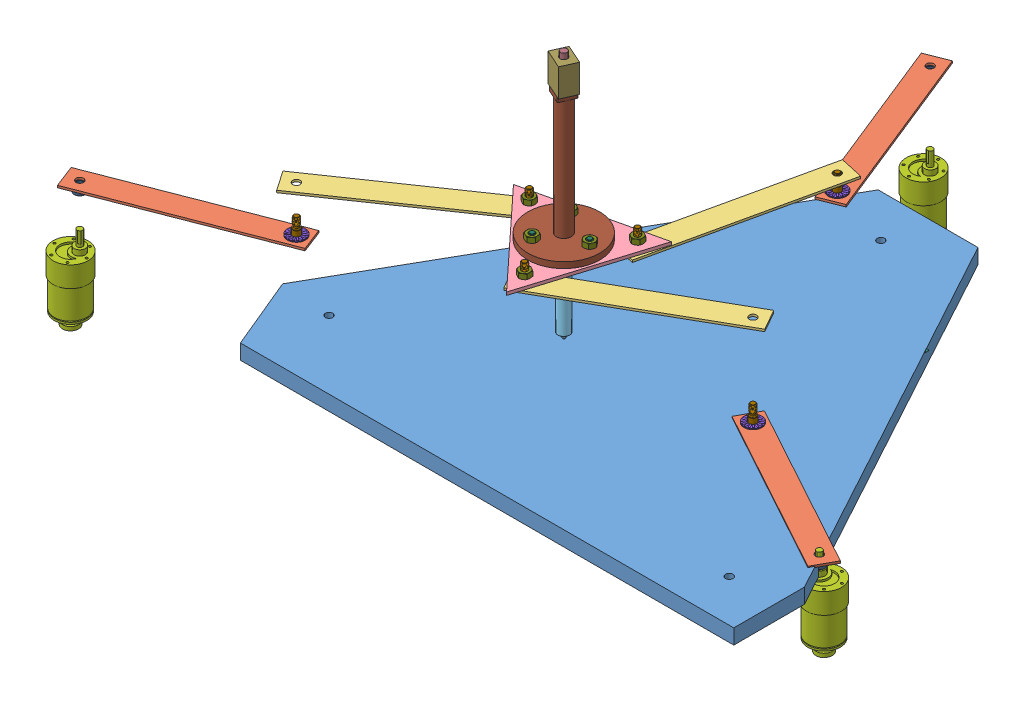
SolidWorks assembly 10_Full_3R_Assembly_rev4, configuration Default. Lengths in mm.
Overall size (748.91 360.76 573.39).
42 component instances, 16 part files, 95 mates.
Components (placement in the parent):
- 01_Base_Plate_rev4-1: 01_Base_Plate_rev4 [Default] at (-311.7855 -6.35 287.7555) size (555.85 15.88 479.43)
- 02_A_Link-1: 02_A_Link [Default] at (-1028.1586 56.8301 289.4507) x (0.932403 0 -0.361422) z (0.361422 0 0.932403) size (203.2 2.29 25.4)
- 03_B_Link-1: 03_B_Link [Default] at (-858.3965 105.6473 226.4186) x (0.824045 0 -0.566525) z (0.566525 0 0.824045) size (203.2 2.29 25.4)
- 02_A_Link-2: 02_A_Link [Default] at (-506.0967 8.3926 95.3531) x (0.877039 0 0.48042) z (-0.48042 0 0.877039) size (203.2 2.29 25.4)
- 03_B_Link-2: 03_B_Link [Default] at (-648.0718 105.6473 195.683) x (0.868786 0 -0.495189) z (0.495189 0 0.868786) size (203.2 2.29 25.4)
- 02_A_Link-3: 02_A_Link [Default] at (-635.8686 90.8532 -268.3939) x (0.373245 0 0.927733) z (0.927733 0 -0.373245) size (203.2 2.29 25.4)
- 03_B_Link-3: 03_B_Link [Default] at (-605.4137 105.6473 101.8075) x (0.216611 0 -0.976258) z (0.976258 0 0.216611) size (203.2 2.29 25.4)
- 04_Platform-1: 04_Platform [Default] at (-732.8839 109.9177 100.5485) x (0.680323 0 0.732913) z (-0.732913 0 0.680323) size (139.95 3.17 121.2)
- 05_Pen-1: 05_Pen [Default] at (-655.6663 21.9604 124.3496) x (-0.946735 0 0.322013) z (-0.322013 0 -0.946735) size (12.7 123.83 12.7)
- 06_Paper-1: 06_Paper [Default] at (-679.8568 8.7347 207.5281) size (215.9 0.25 279.4)
- 07_Motor_rev2-1: 07_Motor_rev2 [Default] at (-649.9106 -74.05 -251.8611) x (0 -1 0) z (0.001482 0 0.999999) size (88.7 37 37)
- 07_Motor_rev2-2: 07_Motor_rev2 [Default] at (-1026.5606 -74.05 277.1468) x (0 -1 0) z (0.589672 0 0.807643) size (88.7 37 37)
- 07_Motor_rev2-3: 07_Motor_rev2 [Default] at (-326.1577 -74.05 177.5449) x (0 -1 0) z (0.25861 0 -0.965982) size (88.7 37 37)
- 5909K24_Needle-Roller Thrust Bearing-1: 5909K24_Needle-Roller Thrust Bearing [5909K24] at (-576.5477 91.8454 -86.9206) x (-0.973754 0 -0.227603) z (0.227603 0 -0.973754) size (19.05 1.98 19.05)
- 91259A576_Alloy Steel Shoulder Screw-1: 91259A576_Alloy Steel Shoulder Screw [91259A576] at (-576.5477 83.0109 -86.9206) x (0.154475 0 0.987997) z (0 -1 0) size (11.11 11.11 26.95)
- 5909K24_Needle-Roller Thrust Bearing-3: 5909K24_Needle-Roller Thrust Bearing [5909K24] at (-855.1259 60.1083 208.7584) x (0.9423 0 0.334769) z (-0.334769 0 0.9423) size (19.05 1.98 19.05)
- 5909K24_Needle-Roller Thrust Bearing-4: 5909K24_Needle-Roller Thrust Bearing [5909K24] at (-488.857 11.6708 90.316) x (0.999962 0 -0.008701) z (0.008701 0 0.999962) size (19.05 1.98 19.05)
- 91259A576_Alloy Steel Shoulder Screw-2: 91259A576_Alloy Steel Shoulder Screw [91259A576] at (-855.1259 51.2739 208.7584) x (0.890655 0 -0.45468) z (0 -1 0) size (11.11 11.11 26.95)
- 91259A576_Alloy Steel Shoulder Screw-3: 91259A576_Alloy Steel Shoulder Screw [91259A576] at (-488.857 2.8363 90.316) x (0.621536 0 -0.783386) z (0 -1 0) size (11.11 11.11 26.95)
- 91259A576_Alloy Steel Shoulder Screw-4: 91259A576_Alloy Steel Shoulder Screw [91259A576] at (-708.6108 100.091 108.0303) x (-0.287715 0 -0.957716) z (0 -1 0) size (11.11 11.11 26.95)
- 91259A576_Alloy Steel Shoulder Screw-5: 91259A576_Alloy Steel Shoulder Screw [91259A576] at (-643.3271 100.091 178.3605) x (0.554326 0 -0.8323) z (0 -1 0) size (11.11 11.11 26.95)
- 91259A576_Alloy Steel Shoulder Screw-6: 91259A576_Alloy Steel Shoulder Screw [91259A576] at (-615.0612 100.091 86.6581) x (0.999981 0 0.006147) z (0 -1 0) size (11.11 11.11 26.95)
- 5909K24_Needle-Roller Thrust Bearing-5: 5909K24_Needle-Roller Thrust Bearing [5909K24] at (-708.6108 108.9255 108.0303) x (0.997045 0 0.076824) z (-0.076824 0 0.997045) size (19.05 1.98 19.05)
- 5909K24_Needle-Roller Thrust Bearing-6: 5909K24_Needle-Roller Thrust Bearing [5909K24] at (-615.0612 108.9255 86.6581) x (0.994154 0 -0.107968) z (0.107968 0 0.994154) size (19.05 1.98 19.05)
- 5909K24_Needle-Roller Thrust Bearing-7: 5909K24_Needle-Roller Thrust Bearing [5909K24] at (-643.3271 108.9255 178.3605) x (0.969179 0 -0.246358) z (0.246358 0 0.969179) size (19.05 1.98 19.05)
- 6056N14_Carbon Steel Set Screw Collar-1: 6056N14_Carbon Steel Set Screw Collar [6056N14] at (-1020.9071 52.8301 273.0191) x (-0.584369 0 0.811488) z (0 1 0) size (12 12.47 8)
- 6056N14_Carbon Steel Set Screw Collar-2: 6056N14_Carbon Steel Set Screw Collar [6056N14] at (-642.9106 84.5672 -251.8715) x (0.948137 0 -0.317863) z (0 1 0) size (12 12.47 8)
- 6056N14_Carbon Steel Set Screw Collar-3: 6056N14_Carbon Steel Set Screw Collar [6056N14] at (-332.9195 4.3926 175.7347) x (0.999426 0 0.033886) z (0 -1 0) size (12 12.47 8)
- PenHolder-1: PenHolder [Default] at (-655.6663 113.0927 124.3496) x (-0.407207 0 0.913336) z (-0.913336 0 -0.407207) size (76.2 138.35 76.2)
- SolenoidAssembly-1: SolenoidAssembly [Default] at (-617.3347 234.5732 124.9461) x (-0.407207 0 0.913336) z (-0.913336 0 -0.407207) size (17 55.9 22)
  - Solenoid_Mount-2: Solenoid_Mount [Default] at (6.5641 46.5695 46.2525) x (1 0 0) z (0 0 -1) size (17 29.7 22)
  - Solenoid_Shaft-1: Solenoid_Shaft [Default] at (15.0641 0.2373 35.2525) x (-0.773677 0 0.63358) z (-0.63358 0 -0.773677) size (6.9 51.9 6.9)
  - Solenoid_Cap-1: Solenoid_Cap [Default] at (15.0641 -3.7627 35.2525) x (0.200587 0 -0.979676) z (0.979676 0 0.200587) size (5 12 5)
- 90604A539_Pan Head Combination Phillips Slotted Screws-1: 90604A539_Pan Head Combination Phillips Slotted Screws [90604A539] at (-670.1692 125.7927 103.4971) x (-0.886591 0 -0.462554) z (0 -1 0) size (12.5 12.5 20.66)
- 90604A539_Pan Head Combination Phillips Slotted Screws-2: 90604A539_Pan Head Combination Phillips Slotted Screws [90604A539] at (-666.4738 125.7927 147.3357) x (0.746863 0 0.664978) z (0 -1 0) size (12.5 12.5 20.66)
- 90604A539_Pan Head Combination Phillips Slotted Screws-3: 90604A539_Pan Head Combination Phillips Slotted Screws [90604A539] at (-630.3561 125.7927 122.2161) x (1 0 0) z (0 -1 0) size (12.5 12.5 20.66)
- 95462A029_Medium-Strength Steel Hex Nut-1: 95462A029_Medium-Strength Steel Hex Nut [95462A029] at (-630.3561 122.2208 122.2161) x (-0.145713 0 -0.989327) z (0 -1 0) size (11.11 12.83 6.51)
- 95462A029_Medium-Strength Steel Hex Nut-2: 95462A029_Medium-Strength Steel Hex Nut [95462A029] at (-643.3271 115.8708 178.3605) x (-1 0 0) z (0 1 0) size (11.11 12.83 6.51)
- 95462A029_Medium-Strength Steel Hex Nut-3: 95462A029_Medium-Strength Steel Hex Nut [95462A029] at (-670.1692 122.2208 103.4971) x (-1 0 0) z (0 1 0) size (11.11 12.83 6.51)
- 95462A029_Medium-Strength Steel Hex Nut-4: 95462A029_Medium-Strength Steel Hex Nut [95462A029] at (-708.6108 115.8708 108.0303) x (-1 0 0) z (0 1 0) size (11.11 12.83 6.51)
- 95462A029_Medium-Strength Steel Hex Nut-5: 95462A029_Medium-Strength Steel Hex Nut [95462A029] at (-615.0612 115.8708 86.6581) x (-1 0 0) z (0 1 0) size (11.11 12.83 6.51)
- 95462A029_Medium-Strength Steel Hex Nut-6: 95462A029_Medium-Strength Steel Hex Nut [95462A029] at (-666.4738 122.2208 147.3357) x (-0.377684 0 0.925934) z (0 -1 0) size (11.11 12.83 6.51)
Mates (geometry in assembly coordinates):
- Concentric4: concentric anti-aligned: circle of 04_Platform-1; circle of 05_Pen-1
- Tangent1: tangent anti-aligned: plane of 06_Paper-1 through (-679.8568 8.9887 207.5281) normal (0 1 0); sphere of 08_Roller-1
- Tangent2: tangent anti-aligned: plane of 06_Paper-1 through (-679.8568 8.9887 207.5281) normal (0 1 0); sphere of 08_Roller-2
- Tangent3: tangent anti-aligned: plane of 06_Paper-1 through (-679.8568 8.9887 207.5281) normal (0 1 0); sphere of 08_Roller-3
- Tangent4: tangent anti-aligned: plane of 04_Platform-1 through (-732.8839 109.9177 100.5485) normal (0 -1 0); sphere of 08_Roller-1
- Coincident37: coincident anti-aligned: plane of 02_A_Link-3 through (-635.8686 88.5672 -268.3939) normal (0 -1 0); plane of 07_Motor-3 through (15.6523 48.5738 -175.9022) normal (0 1 0)
- Concentric8: concentric aligned: circle of 02_A_Link-3; circle of 07_Motor-3
- Concentric12: concentric anti-aligned: circle of 04_Platform-1; circle of 10_Ball_Transfer-2/09_Ball_Holder-1
- Concentric23: concentric anti-aligned: circle of 02_A_Link-1; circle of 07_Motor_rev2-2
- Concentric24: concentric anti-aligned: circle of 02_A_Link-2; circle of 07_Motor_rev2-3
- Concentric25: concentric aligned: circle of 02_A_Link-3; circle of 07_Motor_rev2-1
- Concentric26: concentric anti-aligned: cylinder of 07_Motor_rev2-1 through (-649.9106 6.0614 -251.8611) axis (0 1 0) radius 18.5; cylinder of Motor_Mount-1 through (18.4145 -100.9975 -177.0726) axis (0 -1 0) radius 20.6375
- Concentric29: concentric aligned: cylinder of 03_B_Link-3 through (-576.5477 105.6473 -86.9206) axis (0 1 0) radius 3.9688; cylinder of 91259A427_Alloy Steel Shoulder Screw-1 through (-164.7374 27.7812 -154.398) axis (0 1 0) radius 3.9688
- Concentric30: concentric aligned: cylinder of 02_A_Link-3 through (-576.5477 90.8532 -86.9206) axis (0 -1 0) radius 3.9688; cylinder of 5909K24_Needle-Roller Thrust Bearing-1 through (-576.5477 90.8532 -86.9206) axis (0 -1 0) radius 3.9624
- Tangent7: tangent anti-aligned: plane of 02_A_Link-3 through (-635.8686 90.8532 -268.3939) normal (0 1 0); cylinder of 5909K24_Needle-Roller Thrust Bearing-1 through (-570.1082 91.8454 -80.8828) axis (0.729494 0 0.683987) radius 0.9922
- Coincident58: coincident anti-aligned: plane of 07_Motor_rev2-1 through (-632.6606 -28.25 -251.8867) normal (0 -1 0); plane of Motor_Mount-1 through (3.4631 -22.225 -165.2677) normal (0 1 0)
- Concentric32: concentric anti-aligned: cylinder of 02_A_Link-3 through (-576.5477 90.8532 -86.9206) axis (0 -1 0) radius 3.9688; cylinder of 03_B_Link-3 through (-576.5477 105.6473 -86.9206) axis (0 1 0) radius 3.9688
- Concentric33: concentric anti-aligned: circle of 03_B_Link-3; circle of 5909K24_Needle-Roller Thrust Bearing-2
- Tangent10: tangent anti-aligned: plane of 5909K24_Needle-Roller Thrust Bearing-1 through (-574.3798 92.3415 -96.1956) normal (0 1 0); cylinder of 5909K24_Needle-Roller Thrust Bearing-2 through (-163.8488 16.8055 -163.1804) axis (0.100661 0 -0.994921) radius 0.9922
- Concentric34: concentric aligned: circle of 03_B_Link-3; circle of 91259A175_Alloy Steel Shoulder Screw-1
- Concentric36: concentric aligned: circle of 03_B_Link-3; circle of 91259A576_Alloy Steel Shoulder Screw-1
- Concentric37: concentric aligned: circle of 02_A_Link-2; circle of 03_B_Link-2
- Concentric38: concentric aligned: circle of 02_A_Link-1; circle of 03_B_Link-1
- Concentric39: concentric anti-aligned: cylinder of 02_A_Link-2 through (-488.857 8.3926 90.316) axis (0 1 0) radius 3.9688; cylinder of 5909K24_Needle-Roller Thrust Bearing-4 through (-488.857 10.6786 90.316) axis (0 -1 0) radius 3.9624
- Tangent13: tangent anti-aligned: plane of 02_A_Link-2 through (-506.0967 10.6786 95.3531) normal (0 1 0); cylinder of 5909K24_Needle-Roller Thrust Bearing-4 through (-492.3771 11.6708 98.4111) axis (-0.398773 0 0.91705) radius 0.9922
- Concentric43: concentric anti-aligned: cylinder of 03_B_Link-1 through (-855.1259 105.6473 208.7584) axis (0 1 0) radius 3.9688; cylinder of 5909K24_Needle-Roller Thrust Bearing-3 through (-855.1259 59.1161 208.7584) axis (0 -1 0) radius 3.9624
- Tangent15: tangent anti-aligned: plane of 02_A_Link-1 through (-1028.1586 59.1161 289.4507) normal (0 1 0); cylinder of 5909K24_Needle-Roller Thrust Bearing-3 through (-860.852 60.1083 202.0402) axis (-0.648671 0 -0.761069) radius 0.9922
- Concentric44: concentric aligned: cylinder of 03_B_Link-2 through (-488.857 105.6473 90.316) axis (0 1 0) radius 3.9688; cylinder of 91259A576_Alloy Steel Shoulder Screw-3 through (-488.857 29.0301 90.316) axis (0 1 0) radius 3.9688
- Coincident71: coincident anti-aligned: plane of 02_A_Link-3 through (-635.8686 88.5672 -268.3939) normal (0 -1 0); plane of 91259A576_Alloy Steel Shoulder Screw-1 through (-571.0581 88.5672 -87.7789) normal (0 1 0)
- Coincident72: coincident anti-aligned: plane of 02_A_Link-2 through (-506.0967 8.3926 95.3531) normal (0 -1 0); plane of 91259A576_Alloy Steel Shoulder Screw-3 through (-493.2097 8.3926 86.8626) normal (0 1 0)
- Coincident73: coincident anti-aligned: plane of 02_A_Link-1 through (-1028.1586 56.8301 289.4507) normal (0 -1 0); plane of 91259A576_Alloy Steel Shoulder Screw-2 through (-857.6523 56.8301 203.8097) normal (0 1 0)
- Concentric45: concentric aligned: cylinder of 02_A_Link-1 through (-855.1259 56.8301 208.7584) axis (0 1 0) radius 3.9688; cylinder of 91259A576_Alloy Steel Shoulder Screw-2 through (-855.1259 77.4676 208.7584) axis (0 1 0) radius 3.9688
- Concentric46: concentric aligned: cylinder of 07_Motor_rev2-2 through (-1020.9071 -74.05 273.0191) axis (0 -1 0) radius 3; cylinder of 98541A114_External Retaining Ring-1 through (-200.6826 18.389 208.8764) axis (0 -1 0) radius 2.8
- Coincident74: coincident anti-aligned: plane of 02_A_Link-1 through (-1028.1586 56.8301 289.4507) normal (0 -1 0); plane of 98541A114_External Retaining Ring-1 through (-200.6826 18.389 208.8764) normal (0 1 0)
- Concentric49: concentric anti-aligned: cylinder of 03_B_Link-2 through (-643.3271 105.6473 178.3605) axis (0 1 0) radius 3.9688; cylinder of 04_Platform-1 through (-643.3271 113.0927 178.3605) axis (0 -1 0) radius 3.9688
- Concentric50: concentric anti-aligned: cylinder of 03_B_Link-1 through (-708.6108 105.6473 108.0303) axis (0 1 0) radius 3.9688; cylinder of 04_Platform-1 through (-708.6108 113.0927 108.0303) axis (0 -1 0) radius 3.9688
- Concentric51: concentric anti-aligned: cylinder of 03_B_Link-3 through (-615.0612 105.6473 86.6581) axis (0 1 0) radius 3.9688; cylinder of 04_Platform-1 through (-615.0612 113.0927 86.6581) axis (0 -1 0) radius 3.9688
- Coincident78: coincident anti-aligned: plane of 04_Platform-1 through (-732.8839 109.9177 100.5485) normal (0 -1 0); plane of Spacer_Platform-1 through (19.8558 28.0458 18.7709) normal (0 1 0)
- Coincident79: coincident anti-aligned: plane of 10_Ball_Transfer-2/09_Ball_Holder-1 through (-104.8331 16.9333 22.1387) normal (0 1 0); plane of Spacer_Platform-2 through (-4.1341 20.1083 60.3228) normal (0 -1 0)
- Concentric53: concentric anti-aligned: circle of 10_Ball_Transfer-2/09_Ball_Holder-1; circle of Spacer_Platform-2
- Parallel4: parallel anti-aligned: plane of 03_B_Link-2 through (-648.0718 107.9333 195.683) normal (0 1 0); plane of 04_Platform-1 through (-732.8839 109.9177 100.5485) normal (0 -1 0)
- Parallel5: parallel aligned: plane of 03_B_Link-1 through (-858.3965 107.9333 226.4186) normal (0 1 0); plane of 04_Platform-1 through (-732.8839 113.0927 100.5485) normal (0 1 0)
- Parallel6: parallel aligned: plane of 03_B_Link-3 through (-605.4137 107.9333 101.8075) normal (0 1 0); plane of 04_Platform-1 through (-732.8839 113.0927 100.5485) normal (0 1 0)
- Coincident85: coincident anti-aligned: plane of 03_B_Link-1 through (-858.3965 105.6473 226.4186) normal (0 -1 0); plane of 91259A576_Alloy Steel Shoulder Screw-4 through (-713.9321 105.6473 109.6289) normal (0 1 0)
- Concentric55: concentric aligned: cylinder of 03_B_Link-1 through (-708.6108 105.6473 108.0303) axis (0 1 0) radius 3.9688; cylinder of 91259A576_Alloy Steel Shoulder Screw-4 through (-708.6108 126.2848 108.0303) axis (0 1 0) radius 3.9688
- Concentric56: concentric anti-aligned: cylinder of 91259A576_Alloy Steel Shoulder Screw-4 through (-708.6108 126.2848 108.0303) axis (0 1 0) radius 3.9688; cylinder of 5909K24_Needle-Roller Thrust Bearing-5 through (-708.6108 107.9333 108.0303) axis (0 -1 0) radius 3.9624
- Tangent20: tangent anti-aligned: plane of 03_B_Link-1 through (-858.3965 107.9333 226.4186) normal (0 1 0); cylinder of 5909K24_Needle-Roller Thrust Bearing-5 through (-715.6051 108.9255 113.4155) axis (-0.792354 0 0.610061) radius 0.9922
- Concentric57: concentric anti-aligned: cylinder of 04_Platform-1 through (-643.3271 113.0927 178.3605) axis (0 -1 0) radius 3.9688; cylinder of 91259A576_Alloy Steel Shoulder Screw-5 through (-643.3271 126.2848 178.3605) axis (0 1 0) radius 3.9688
- Coincident86: coincident anti-aligned: plane of 03_B_Link-2 through (-648.0718 105.6473 195.683) normal (0 -1 0); plane of 91259A576_Alloy Steel Shoulder Screw-5 through (-647.9516 105.6473 175.2806) normal (0 1 0)
- Concentric58: concentric anti-aligned: cylinder of 04_Platform-1 through (-615.0612 113.0927 86.6581) axis (0 -1 0) radius 3.9688; cylinder of 91259A576_Alloy Steel Shoulder Screw-6 through (-615.0612 126.2848 86.6581) axis (0 1 0) radius 3.9688
- Concentric59: concentric anti-aligned: cylinder of 91259A576_Alloy Steel Shoulder Screw-5 through (-643.3271 126.2848 178.3605) axis (0 1 0) radius 3.9688; cylinder of 5909K24_Needle-Roller Thrust Bearing-7 through (-643.3271 107.9333 178.3605) axis (0 -1 0) radius 3.9624
- Tangent24: tangent anti-aligned: plane of 03_B_Link-2 through (-648.0718 107.9333 195.683) normal (0 1 0); cylinder of 5909K24_Needle-Roller Thrust Bearing-7 through (-641.1524 108.9255 186.9158) axis (0.246358 0 0.969179) radius 0.9922
- Concentric60: concentric anti-aligned: cylinder of 91259A576_Alloy Steel Shoulder Screw-6 through (-615.0612 126.2848 86.6581) axis (0 1 0) radius 3.9688; cylinder of 5909K24_Needle-Roller Thrust Bearing-6 through (-615.0612 107.9333 86.6581) axis (0 -1 0) radius 3.9624
- Tangent25: tangent anti-aligned: plane of 03_B_Link-3 through (-605.4137 107.9333 101.8075) normal (0 1 0); cylinder of 5909K24_Needle-Roller Thrust Bearing-6 through (-606.4332 108.9255 84.7929) axis (0.977423 0 -0.211294) radius 0.9922
- Coincident88: coincident anti-aligned: plane of 03_B_Link-3 through (-605.4137 105.6473 101.8075) normal (0 -1 0); plane of 91259A576_Alloy Steel Shoulder Screw-6 through (-615.027 105.6473 81.1019) normal (0 1 0)
- Concentric61: concentric anti-aligned: cylinder of 07_Motor_rev2-1 through (-642.9106 -74.05 -251.8715) axis (0 -1 0) radius 3; cylinder of grainger-2alx5-1 through (24.5848 9.389 -180.3783) axis (0 1 0) radius 1.5
- Coincident89: coincident anti-aligned: plane of 02_A_Link-3 through (-635.8686 88.5672 -268.3939) normal (0 -1 0); plane of grainger-2alx5-1 through (24.5848 18.389 -180.3783) normal (0 1 0)
- Concentric62: concentric anti-aligned: cylinder of 07_Motor_rev2-3 through (-332.9195 -74.05 175.7347) axis (0 -1 0) radius 3; cylinder of grainger-2alx5-2 through (238.4578 9.389 207.6961) axis (0 1 0) radius 1.5
- Coincident90: coincident anti-aligned: plane of 02_A_Link-2 through (-506.0967 8.3926 95.3531) normal (0 -1 0); plane of grainger-2alx5-2 through (238.4578 18.389 207.6961) normal (0 1 0)
- Concentric63: concentric anti-aligned: cylinder of 07_Motor_rev2-2 through (-1020.9071 -74.05 273.0191) axis (0 -1 0) radius 3; cylinder of grainger-2alx5-3 through (-199.783 9.389 210.9877) axis (0 1 0) radius 1.5
- Coincident91: coincident anti-aligned: plane of 02_A_Link-1 through (-1028.1586 56.8301 289.4507) normal (0 -1 0); plane of grainger-2alx5-3 through (-199.783 18.389 210.9877) normal (0 1 0)
- Concentric64: concentric aligned: cylinder of 07_Motor_rev2-2 through (-1020.9071 -74.05 273.0191) axis (0 -1 0) radius 3; cylinder of 6056N14_Carbon Steel Set Screw Collar-1 through (-1020.9071 56.8301 273.0191) axis (0 -1 0) radius 3
- Coincident92: coincident anti-aligned: plane of 02_A_Link-1 through (-1028.1586 56.8301 289.4507) normal (0 -1 0); plane of 6056N14_Carbon Steel Set Screw Collar-1 through (-1020.9071 56.8301 273.0191) normal (0 1 0)
- Concentric65: concentric anti-aligned: cylinder of 07_Motor_rev2-3 through (-332.9195 -74.05 175.7347) axis (0 -1 0) radius 3; cylinder of 6056N14_Carbon Steel Set Screw Collar-3 through (-332.9195 0.3926 175.7347) axis (0 1 0) radius 3
- Coincident93: coincident anti-aligned: plane of 02_A_Link-2 through (-506.0967 8.3926 95.3531) normal (0 -1 0); plane of 6056N14_Carbon Steel Set Screw Collar-3 through (-332.9195 8.3926 175.7347) normal (0 1 0)
- Concentric66: concentric aligned: cylinder of 07_Motor_rev2-1 through (-642.9106 -74.05 -251.8715) axis (0 -1 0) radius 3; cylinder of 6056N14_Carbon Steel Set Screw Collar-2 through (-642.9106 88.5672 -251.8715) axis (0 -1 0) radius 3
- Coincident94: coincident anti-aligned: plane of 02_A_Link-3 through (-635.8686 88.5672 -268.3939) normal (0 -1 0); plane of 6056N14_Carbon Steel Set Screw Collar-2 through (-642.9106 88.5672 -251.8715) normal (0 1 0)
- Coincident97: coincident anti-aligned: plane of 04_Platform-1 through (-732.8839 109.9177 100.5485) normal (0 -1 0); plane of 92510A763_Aluminum Unthreaded Spacer-1 through (-8.7932 25.1248 -129.4012) normal (0 1 0)
- Coincident98: coincident aligned: circle of 10_Ball_Transfer-2/09_Ball_Holder-1; circle of 92510A763_Aluminum Unthreaded Spacer-2
- Concentric68: concentric aligned: cylinder of 05_Pen-1 through (-655.6663 21.9604 124.3496) axis (0 -1 0) radius 6.35; cylinder of PenHolder-1 through (-655.6663 266.6482 124.3496) axis (0 -1 0) radius 7.1437
- Coincident101: coincident anti-aligned: plane of 04_Platform-1 through (-732.8839 113.0927 100.5485) normal (0 1 0); plane of PenHolder-1 through (-655.6663 113.0927 124.3496) normal (0 -1 0)
- Concentric69: concentric aligned: cylinder of PenHolder-1 through (-655.6663 113.0927 124.3496) axis (0 1 0) radius 3; cylinder of SolenoidAssembly-1/Solenoid_Cap-1 through (-655.6663 351.585 124.3496) axis (0 1 0) radius 2.5
- Coincident102: coincident anti-aligned: plane of PenHolder-1 through (-655.6663 251.4427 124.3496) normal (0 1 0); plane of SolenoidAssembly-1/Solenoid_Mount-2 through (-642.1584 251.4427 121.0656) normal (0 -1 0)
- Concentric70: concentric anti-aligned: circle of PenHolder-1; circle of 90604A539_Pan Head Combination Phillips Slotted Screws-1
- Coincident103: coincident anti-aligned: plane of 04_Platform-1 through (-732.8839 109.9177 100.5485) normal (0 -1 0); plane of 90604A539_Pan Head Combination Phillips Slotted Screws-1 through (-672.6893 109.9177 108.3275) normal (0 1 0)
- Concentric71: concentric anti-aligned: circle of PenHolder-1; circle of 90604A539_Pan Head Combination Phillips Slotted Screws-2
- Coincident104: coincident anti-aligned: plane of 04_Platform-1 through (-732.8839 109.9177 100.5485) normal (0 -1 0); plane of 90604A539_Pan Head Combination Phillips Slotted Screws-2 through (-662.8508 109.9177 143.2666) normal (0 1 0)
- Concentric72: concentric anti-aligned: circle of PenHolder-1; circle of 90604A539_Pan Head Combination Phillips Slotted Screws-3
- Coincident105: coincident anti-aligned: plane of 04_Platform-1 through (-732.8839 109.9177 100.5485) normal (0 -1 0); plane of 90604A539_Pan Head Combination Phillips Slotted Screws-3 through (-630.3561 109.9177 116.7678) normal (0 1 0)
- Coincident106: coincident anti-aligned: plane of PenHolder-1 through (-671.181 119.4427 159.1477) normal (0 1 0); plane of 95462A029_Medium-Strength Steel Hex Nut-1 through (-626.3728 119.4427 127.2456) normal (0 -1 0)
- Concentric73: concentric anti-aligned: circle of 90604A539_Pan Head Combination Phillips Slotted Screws-3; circle of 95462A029_Medium-Strength Steel Hex Nut-1
- Concentric74: concentric aligned: circle of 90604A539_Pan Head Combination Phillips Slotted Screws-1; circle of 95462A029_Medium-Strength Steel Hex Nut-3
- Coincident109: coincident anti-aligned: plane of PenHolder-1 through (-671.181 119.4427 159.1477) normal (0 1 0); plane of 95462A029_Medium-Strength Steel Hex Nut-3 through (-664.6129 119.4427 106.705) normal (0 -1 0)
- Concentric75: concentric aligned: circle of 91259A576_Alloy Steel Shoulder Screw-5; circle of 95462A029_Medium-Strength Steel Hex Nut-2
- Coincident110: coincident anti-aligned: plane of 04_Platform-1 through (-732.8839 113.0927 100.5485) normal (0 1 0); plane of 95462A029_Medium-Strength Steel Hex Nut-2 through (-637.7708 113.0927 181.5684) normal (0 -1 0)
- Concentric76: concentric aligned: circle of 91259A576_Alloy Steel Shoulder Screw-4; circle of 95462A029_Medium-Strength Steel Hex Nut-4
- Coincident112: coincident anti-aligned: plane of 04_Platform-1 through (-732.8839 113.0927 100.5485) normal (0 1 0); plane of 95462A029_Medium-Strength Steel Hex Nut-4 through (-703.0545 113.0927 111.2382) normal (0 -1 0)
- Concentric77: concentric aligned: circle of 91259A576_Alloy Steel Shoulder Screw-6; circle of 95462A029_Medium-Strength Steel Hex Nut-5
- Coincident113: coincident anti-aligned: plane of 04_Platform-1 through (-732.8839 113.0927 100.5485) normal (0 1 0); plane of 95462A029_Medium-Strength Steel Hex Nut-5 through (-609.5049 113.0927 89.866) normal (0 -1 0)
- Coincident114: coincident anti-aligned: plane of PenHolder-1 through (-671.181 119.4427 159.1477) normal (0 1 0); plane of 95462A029_Medium-Strength Steel Hex Nut-6 through (-667.3456 119.4427 140.9794) normal (0 -1 0)
- Concentric78: concentric anti-aligned: circle of 90604A539_Pan Head Combination Phillips Slotted Screws-2; circle of 95462A029_Medium-Strength Steel Hex Nut-6
- Parallel8: parallel aligned: line of PenHolder-1 through (-645.3551 251.4427 119.6403) axis (-0.913336 0 -0.407207); line of SolenoidAssembly-1/Solenoid_Mount-2 through (-642.1584 251.4427 121.0656) axis (-0.913336 0 -0.407207)
- Tangent28: tangent anti-aligned: plane of 04_Platform-1 through (-732.8839 109.9177 100.5485) normal (0 -1 0); cylinder of 5909K24_Needle-Roller Thrust Bearing-5 through (-705.6505 108.9255 116.3464) axis (0.335352 0 0.942093) radius 0.9922
- Tangent29: tangent anti-aligned: plane of 04_Platform-1 through (-732.8839 109.9177 100.5485) normal (0 -1 0); cylinder of 5909K24_Needle-Roller Thrust Bearing-7 through (-635.5142 108.9255 182.469) axis (0.885086 0 0.465428) radius 0.9922
- Tangent30: tangent anti-aligned: plane of 04_Platform-1 through (-732.8839 109.9177 100.5485) normal (0 -1 0); cylinder of 5909K24_Needle-Roller Thrust Bearing-6 through (-607.9377 108.9255 81.4448) axis (0.806979 0 -0.59058) radius 0.9922
